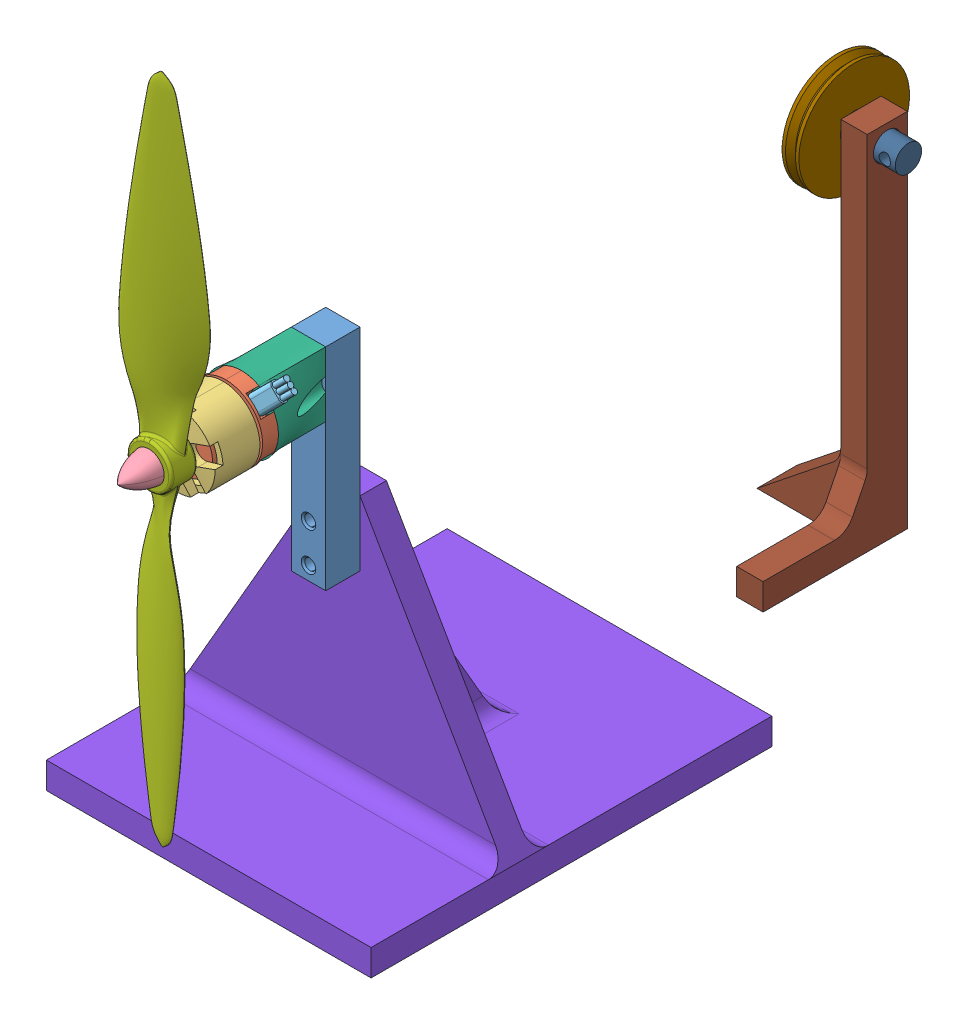
SolidWorks assembly thrust stand, configuration Default. Lengths in mm.
Overall size (122.99 275.42 296.85).
12 component instances, 11 part files, 15 mates.
Components (placement in the parent):
- loadcell-2: loadcell [Default] at (38.5157 1.1572 54.1719) x (0 1 0) z (1 0 0) size (80 13 13)
- User Library-emaxmodel-mt2213.STEP-1: User Library-emaxmodel-mt2213.STEP [Default] at (32.0157 68.8382 92.5719) x (-1 0 0) z (0 1 0) size (36.98 47 36.98)
  - emaxmodel-mt2213-stator_По умолчанию.STEP-1: emaxmodel-mt2213-stator_По умолчанию.STEP [Default] at origin size (28 21 28)
  - emaxmodel-mt2213-rotor_По умолчанию.STEP-1: emaxmodel-mt2213-rotor_По умолчанию.STEP [Default] at (0 7 0) x (0.999557 0 0.02976) z (-0.02976 0 0.999557) size (28 32 28)
  - emaxmodel-mt2213-cone_По умолчанию.STEP-1: emaxmodel-mt2213-cone_По умолчанию.STEP [Default] at (0 32 0) size (12 15 13.86)
  - wires_По умолчанию.STEP-1: wires_По умолчанию.STEP [Default] at (-15.8508 1.5 15.8508) x (0.707107 0 0.707107) z (-0.707107 0 0.707107) size (7 3 19)
- adapter-1: adapter [Default] at (32.0157 68.8382 92.5719) x (1 0 0) z (0 0 -1) size (28.02 28.02 26.93)
- Propeller 10x45.step-1: Propeller 10x45.step [Default] at (32.0157 68.8382 122.5909) x (-1 0 0) z (0 1 0) size (28.85 11.2 254.24)
- support-1: support [Default] at (38.5157 1.1572 54.1719) x (0 -1 0) z (0 0 -1) size (105.25 122.99 151.79)
- pulley-1: pulley [Default] at origin size (6.35 41.91 41.91)
- shaft-1: shaft [Default] at origin size (34.88 10 10)
- pulley support-1: pulley support [Default] at origin size (41.75 136.92 54.69)
Mates (geometry in assembly coordinates):
- Parallel1: parallel anti-aligned: plane of loadcell-2 through (38.5157 1.1572 67.1719) normal (0 0 1); plane of User Library-emaxmodel-mt2213.STEP-1/emaxmodel-mt2213-stator_По умолчанию.STEP-1 through (32.0157 68.8382 92.5719) normal (0 0 -1)
- Width1: width: plane of loadcell-2 through (38.5157 1.1572 67.1719) normal (1 0 0); plane of loadcell-2 through (25.5157 1.1572 67.1719) normal (-1 0 0); cylinder of User Library-emaxmodel-mt2213.STEP-1/emaxmodel-mt2213-stator_По умолчанию.STEP-1 through (32.0157 68.8382 113.5719) axis (0 0 -1) radius 4
- Distance2: distance = 25.4 mm anti-aligned: plane of User Library-emaxmodel-mt2213.STEP-1/emaxmodel-mt2213-stator_По умолчанию.STEP-1 through (32.0157 68.8382 92.5719) normal (0 0 -1); plane of loadcell-2 through (38.5157 1.1572 67.1719) normal (0 0 1)
- Distance5: distance = 12.319 mm: plane of loadcell-2 through (38.5157 81.1572 67.1719) normal (0 1 0); cylinder of User Library-emaxmodel-mt2213.STEP-1/emaxmodel-mt2213-stator_По умолчанию.STEP-1 through (32.0157 68.8382 113.5719) axis (0 0 -1) radius 4
- Angle3: planar angle = 0.785398 rad aligned: plane of loadcell-2 through (38.5157 1.1572 67.1719) normal (1 0 0); plane of User Library-emaxmodel-mt2213.STEP-1/emaxmodel-mt2213-stator_По умолчанию.STEP-1 through (41.6921 84.1714 97.5719) normal (0.707107 -0.707107 0)
- InPlace1: in place: plane of ? through (32.0157 69.524 92.5719) normal (0 0 -1); plane of ? through (0 0 92.5719) normal (0 0 -1); moOrthogonalPlaneRef_w of ? through (32.0157 69.524 92.5719) normal (0 0 -1); plane of ? through (0 0 92.5719) normal (0 1 0); plane of ? through (32.0157 69.524 92.5719) normal (0 0 -1); plane of ? through (0 0 92.5719) normal (-1 0 0); plane of User Library-emaxmodel-mt2213.STEP-1/emaxmodel-mt2213-stator_По умолчанию.STEP-1 through (32.0157 68.8382 92.5719) normal (0 0 -1); unknown of adapter-1
- Coincident4: coincident aligned: plane of User Library-emaxmodel-mt2213.STEP-1/emaxmodel-mt2213-stator_По умолчанию.STEP-1; plane of adapter-1
- Coincident5: coincident aligned: moOrthogonalPlaneRef_w of User Library-emaxmodel-mt2213.STEP-1/emaxmodel-mt2213-stator_По умолчанию.STEP-1 through (32.0157 68.8382 92.5719) normal (0 -1 0); plane of adapter-1 through (32.0157 68.8382 92.5719) normal (0 -1 0)
- Coincident6: coincident anti-aligned: moOrthogonalPlaneRef_w of User Library-emaxmodel-mt2213.STEP-1/emaxmodel-mt2213-stator_По умолчанию.STEP-1 through (32.0157 68.8382 92.5719) normal (-1 0 0); plane of adapter-1 through (32.0157 68.8382 92.5719) normal (1 0 0)
- Concentric1: concentric anti-aligned: cylinder of User Library-emaxmodel-mt2213.STEP-1/emaxmodel-mt2213-rotor_По умолчанию.STEP-1 through (32.0157 68.8382 131.5719) axis (0 0 -1) radius 3; cylinder of Propeller 10x45.step-1 through (32.0157 68.8382 117.5909) axis (0 0 1) radius 3
- Distance7: distance = 25.019 mm anti-aligned: plane of Propeller 10x45.step-1 through (32.0157 68.8382 117.5909) normal (0 0 -1); plane of adapter-1 through (32.0157 68.8382 92.5719) normal (0 0 1)
- Concentric2: concentric aligned: cylinder of loadcell-2 through (32.0157 20.7242 67.1719) axis (0 0 1) radius 2.1; cylinder of support-1 through (32.0157 20.7242 -46.8209) axis (0 0 1) radius 2.8
- Concentric3: concentric aligned: cylinder of loadcell-2 through (32.0157 6.2242 67.1719) axis (0 0 1) radius 2.1; cylinder of support-1 through (32.0157 6.2242 -46.8209) axis (0 0 1) radius 2.8
- Coincident1: coincident anti-aligned: plane of loadcell-2 through (38.5157 1.1572 54.1719) normal (0 0 -1); plane of support-1 through (38.5157 1.1572 54.1719) normal (0 0 1)
- Lock1: lock: unknown of support-1; unknown of pulley-1
